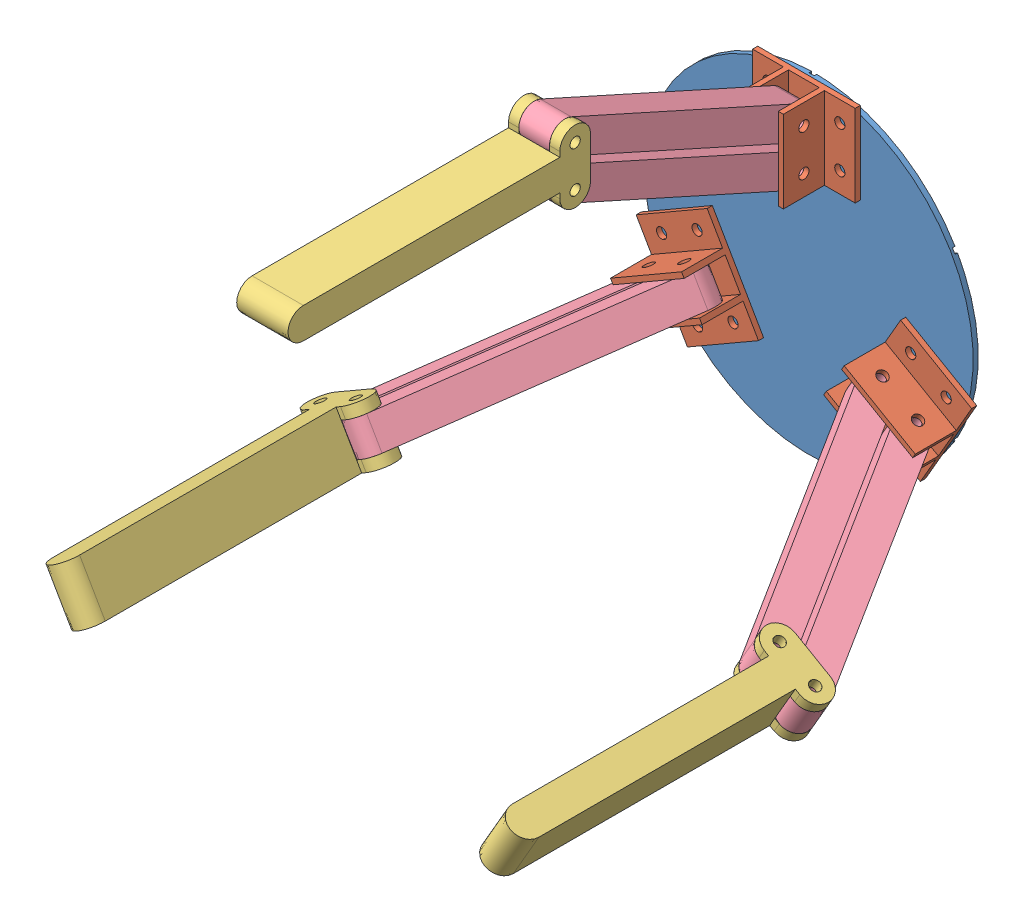
SolidWorks assembly Intake Main Assem, configuration Default. Lengths in mm.
Overall size (336.36 286 341.62).
16 component instances, 4 part files, 9 mates.
Components (placement in the parent):
- Base Plate-1: Base Plate [Default] at origin size (203.2 203.2 3.17)
- Arm Assem-1: Arm Assem [Default] at (-31.75 101.6 3.175) x (1 0 0) z (0 -1 0) size (63.5 338.44 115.84) (flexible)
  - Mounting Bracket-1: Mounting Bracket [Default] at origin size (63.5 28.57 50.8)
  - Contact Arm-1: Contact Arm [Default] at (15.875 160.6445 -52.4409) x (0 1 0) z (1 0 0) size (187.33 44.45 31.75)
  - Parallel Arm-2: Parallel Arm [Default] at (41.275 88.2598 5.5295) x (0 0.911934 -0.410337) z (0 0.410337 0.911934) size (177.8 19.05 19.05)
  - Parallel Arm-3: Parallel Arm [Default] at (41.275 88.2598 -19.8705) x (0 0.911934 -0.410337) z (0 0.410337 0.911934) size (177.8 19.05 19.05)
- Arm Assem-2: Arm Assem [Default] at (103.8632 -23.3037 3.175) x (-0.5 -0.866025 0) z (-0.866025 0.5 0) size (63.5 329.75 133.31) (flexible)
  - Mounting Bracket-1: Mounting Bracket [Default] at origin size (63.5 28.57 50.8)
  - Contact Arm-1: Contact Arm [Default] at (15.875 151.9453 -69.0707) x (0 1 0) z (1 0 0) size (187.33 44.45 31.75)
  - Parallel Arm-2: Parallel Arm [Default] at (41.275 83.9101 -2.7853) x (0 0.857136 -0.515091) z (0 0.515091 0.857136) size (177.8 19.05 19.05)
  - Parallel Arm-3: Parallel Arm [Default] at (41.275 83.9101 -28.1853) x (0 0.857136 -0.515091) z (0 0.515091 0.857136) size (177.8 19.05 19.05)
- Arm Assem-3: Arm Assem [Default] at (-72.1132 -78.2963 3.175) x (-0.5 0.866025 0) z (0.866025 0.5 0) size (63.5 337.85 117.19) (flexible)
  - Mounting Bracket-1: Mounting Bracket [Default] at origin size (63.5 28.57 50.8)
  - Contact Arm-1: Contact Arm [Default] at (15.875 160.0484 -53.7498) x (0 1 0) z (1 0 0) size (187.33 44.45 31.75)
  - Parallel Arm-2: Parallel Arm [Default] at (41.275 87.9617 4.8751) x (0 0.908179 -0.418582) z (0 0.418582 0.908179) size (177.8 19.05 19.05)
  - Parallel Arm-3: Parallel Arm [Default] at (41.275 87.9617 -20.5249) x (0 0.908179 -0.418582) z (0 0.418582 0.908179) size (177.8 19.05 19.05)
Mates (geometry in assembly coordinates):
- Coincident7: coincident: plane of Base Plate-1 through (0 0 3.175) normal (0 0 1); plane of Arm Assem-1/Mounting Bracket-1 through (-31.75 50.8 3.175) normal (0 0 -1)
- Width2: width: plane of Arm Assem-1/Mounting Bracket-1 through (9.525 50.8 31.75) normal (-1 0 0); plane of Arm Assem-1/Mounting Bracket-1 through (-9.525 50.8 6.35) normal (1 0 0); plane of Base Plate-1 through (1.5875 0 1.5875) normal (-1 0 0); plane of Base Plate-1 through (-1.5875 0 1.5875) normal (1 0 0)
- Tangent1: tangent: cylinder of Base Plate-1 through (0 0 3.175) axis (0 0 -1) radius 101.6; plane of Arm Assem-1/Mounting Bracket-1 through (-31.75 101.6 3.175) normal (0 1 0)
- Coincident8: coincident: plane of Base Plate-1 through (0 0 3.175) normal (0 0 1); plane of Arm Assem-2/Mounting Bracket-1 through (59.8691 2.0963 3.175) normal (0 0 -1)
- Coincident9: coincident: plane of Base Plate-1 through (0 0 3.175) normal (0 0 1); plane of Arm Assem-3/Mounting Bracket-1 through (-28.1191 -52.8963 3.175) normal (0 0 -1)
- Width5: width: plane of Arm Assem-2/Mounting Bracket-1 through (39.2316 -33.6489 31.75) normal (0.5 0.866025 0); plane of Arm Assem-2/Mounting Bracket-1 through (48.7566 -17.1511 6.35) normal (-0.5 -0.866025 0); plane of Base Plate-1 through (-0.7937 -1.3748 1.5875) normal (0.5 0.866025 0); plane of Base Plate-1 through (0.7937 1.3748 1.5875) normal (-0.5 -0.866025 0)
- Tangent4: tangent: cylinder of Base Plate-1 through (0 0 3.175) axis (0 0 -1) radius 101.6; plane of Arm Assem-2/Mounting Bracket-1 through (103.8632 -23.3037 3.175) normal (0.866025 -0.5 0)
- Width6: width: plane of Arm Assem-3/Mounting Bracket-1 through (-48.7566 -17.1511 31.75) normal (0.5 -0.866025 0); plane of Arm Assem-3/Mounting Bracket-1 through (-39.2316 -33.6489 6.35) normal (-0.5 0.866025 0); plane of Base Plate-1 through (-0.7937 1.3748 1.5875) normal (0.5 -0.866025 0); plane of Base Plate-1 through (0.7937 -1.3748 1.5875) normal (-0.5 0.866025 0)
- Tangent5: tangent: cylinder of Base Plate-1 through (0 0 3.175) axis (0 0 -1) radius 101.6; plane of Arm Assem-3/Mounting Bracket-1 through (-72.1132 -78.2963 3.175) normal (-0.866025 -0.5 0)
